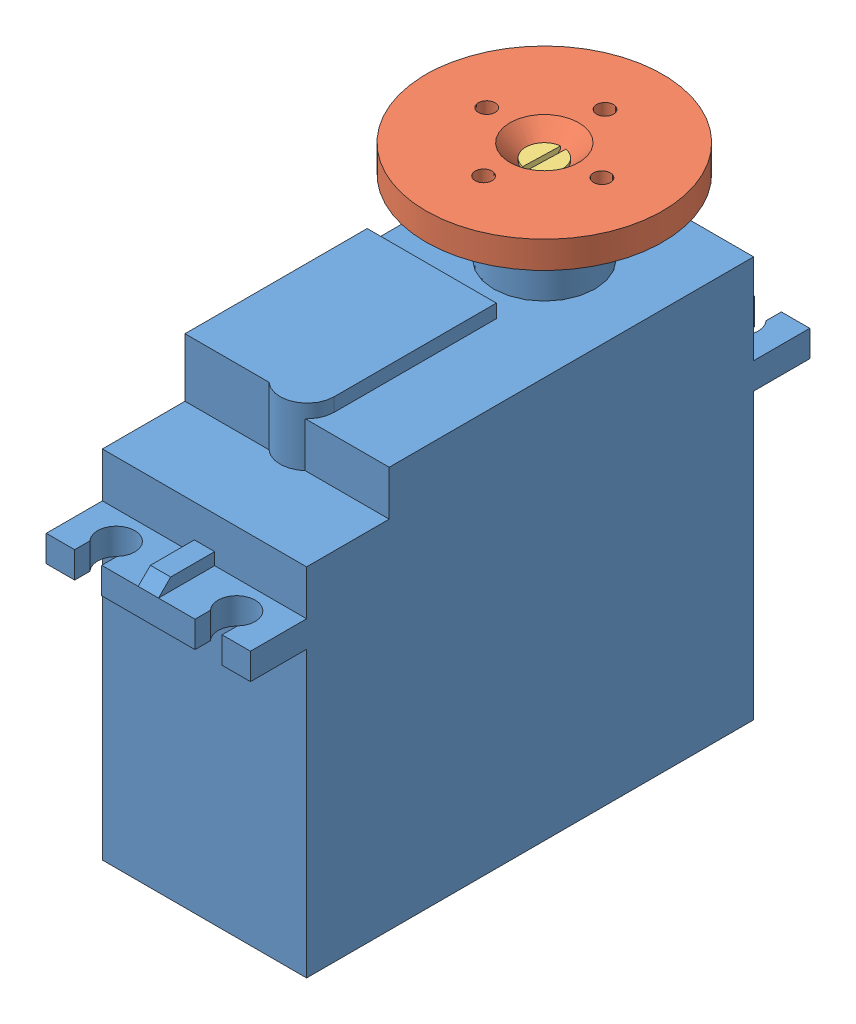
SolidWorks assembly EHT Servo Assembly3, configuration Default. Lengths in mm.
Overall size (35.9 74.3 82.7).
3 component instances, 3 part files, 4 mates.
Components (placement in the parent):
- EHT Servo-1: EHT Servo [Default] at (-5.8382 -48.3416 35.9233) size (30.2 70.3 82.7)
- Servo Fitting1-1: Servo Fitting1 [Default] at (9.2618 21.9584 -14.3267) x (-0.026119 0 0.999659) z (-0.999659 0 -0.026119) size (35 10.9 35)
- slotted countersunk flat head screw_iso-1: slotted countersunk flat head screw_iso [M3x10] at (9.2618 24.0084 -14.3267) x (0 -1 0) z (0.028596 0 -0.999591) size (10 5.5 5.44)
Mates (geometry in assembly coordinates):
- Concentric1: concentric aligned: cylinder of EHT Servo-1 through (9.2618 14.9584 -14.3267) axis (0 1 0) radius 1.75; cylinder of Servo Fitting1-1 through (9.2618 25.9584 -14.3267) axis (0 1 0) radius 1.95
- Coincident4: coincident anti-aligned: plane of EHT Servo-1 through (9.2618 15.0584 -14.3267) normal (0 1 0); plane of Servo Fitting1-1 through (9.2618 15.0584 -14.3267) normal (0 -1 0)
- Coincident10: coincident aligned: cone of Servo Fitting1-1 through (9.2618 25.9584 -14.3267) axis (0 -1 0); cone of slotted countersunk flat head screw_iso-1 through (9.2618 23.6084 -14.3267) axis (0 -1 0)
- Lock4: lock: unknown of Servo Fitting1-1; unknown of slotted countersunk flat head screw_iso-1
